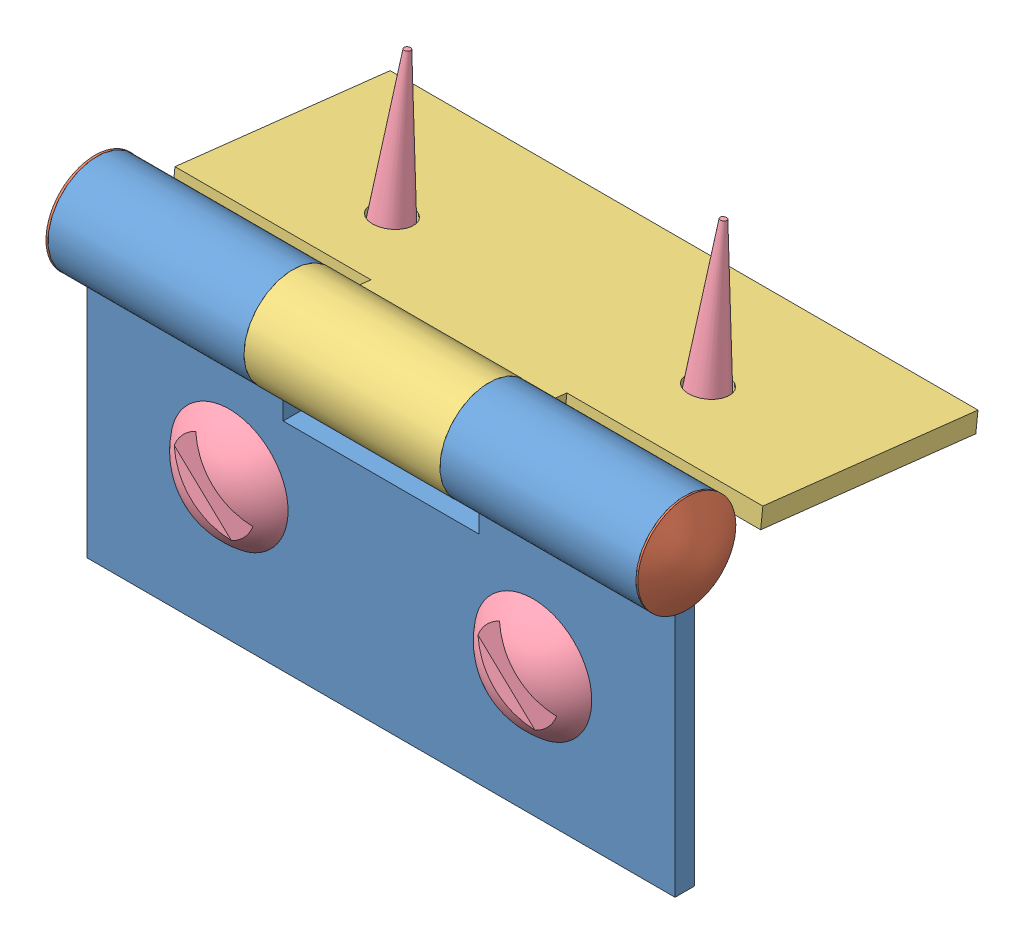
SolidWorks assembly 装配体2, configuration 默认. Lengths in mm.
Overall size (3.22 2.19 1.8).
7 component instances, 4 part files, 8 mates.
Components (placement in the parent):
- 合页1-1: 合页1 [默认] at (-1.4252 -0.1835 0) size (3 1.75 0.5)
- 合页3-1: 合页3 [默认] at (-1.4252 -0.1835 0.05) size (3.22 0.51 0.51)
- 合页2-1: 合页2 [默认] at (-1.4252 0.4322 -0.7396) x (1 0 0) z (0 -0.993615 0.112826) size (3 1.75 0.5)
- 钉-1: 钉 [默认] at (0.8498 0.4218 -0.8319) x (1 0 0) z (0 -0.112826 -0.993615) size (0.6 0.94 0.6)
- 钉-2: 钉 [默认] at (-0.7002 0.4289 -0.769) x (1 0 0) z (0 -0.112826 -0.993615) size (0.6 0.94 0.6)
- 钉-3: 钉 [默认] at (0.8498 -0.2763 0.05) x (1 0 0) z (0 -1 0) size (0.6 0.94 0.6)
- 钉-4: 钉 [默认] at (-0.7002 -0.2131 0.05) x (1 0 0) z (0 -1 0) size (0.6 0.94 0.6)
Mates (geometry in assembly coordinates):
- 同心1: concentric aligned: cylinder of 合页1-1 through (1.5748 0.5665 0) axis (-1 0 0) radius 0.2; cylinder of 合页3-1 through (1.5748 0.5665 0) axis (-1 0 0) radius 0.2
- 同心2: concentric aligned: cylinder of 合页3-1 through (1.5748 0.5665 0) axis (-1 0 0) radius 0.2; cylinder of 合页2-1 through (1.5748 0.5665 0) axis (-1 0 0) radius 0.2
- 重合1: coincident anti-aligned: plane of 合页1-1 through (1.5748 0.5665 0) normal (1 0 0); plane of 合页3-1 through (1.5748 0.5665 0) normal (-1 0 0)
- 重合2: coincident anti-aligned: plane of 合页1-1 through (-0.4252 -3.2292 3.05) normal (1 0 0); plane of 合页2-1 through (-0.4252 3.7186 0.7257) normal (-1 0 0)
- 重合3: coincident aligned: circle of 合页1-1; circle of 钉-4
- 重合4: coincident aligned: circle of 合页1-1; circle of 钉-3
- 重合5: coincident anti-aligned: circle of 合页2-1; circle of 钉-2
- 重合6: coincident anti-aligned: circle of 合页2-1; circle of 钉-1
